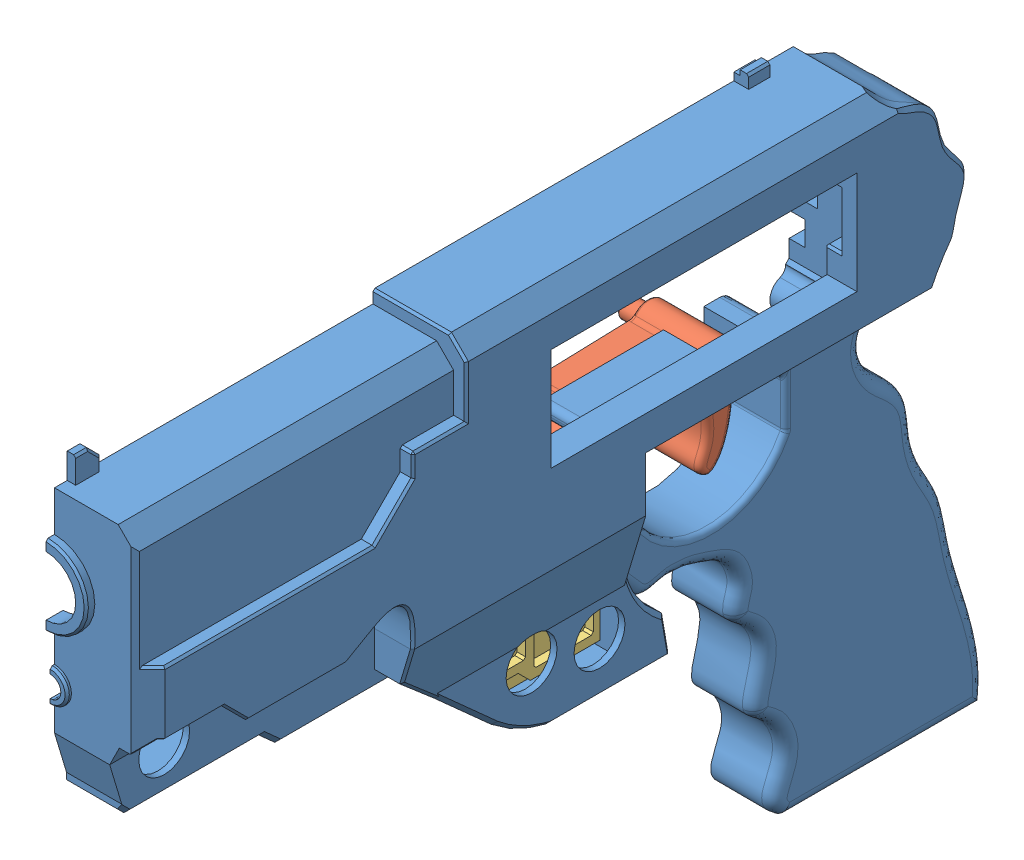
SolidWorks assembly Assemblage_en_coupe, configuration Défaut. Lengths in mm.
Overall size (37.15 144.71 215.3).
5 component instances, 5 part files, 14 mates.
Components (placement in the parent):
- pistolet_cote_circuit-1: pistolet_cote_circuit [Défaut] at (-61.6819 55.6164 215.3016) size (23.45 144.71 215.3)
- gachette_v3-1: gachette_v3 [Défaut] at (-61.6819 30.8475 67.1148) x (0 -0.031257 0.999511) z (-1 0 0) size (42.56 30.73 27.4)
- plaque_interrupteur_crosse-1: plaque_interrupteur_crosse [Défaut] at (-55.1819 -2.708 116.1316) x (0 0 1) z (-1 0 0) size (47.34 21.79 4)
- plaque_interrupteur_canon-1: plaque_interrupteur_canon [Défaut] at (-59.1819 21.0092 190.2537) x (0 0 1) z (-1 0 0) size (32.24 14.2 3.5)
- coulisseau_v3-1: coulisseau_v3 [Défaut] at (-62.3819 55.6164 150.3016) x (0 -1 0) z (0 0 -1) size (29 16 7)
Mates (geometry in assembly coordinates):
- Coaxiale1: concentric aligned: cylinder of pistolet_cote_circuit-1 through (-76.1819 30.8475 67.1148) axis (1 0 0) radius 2.7; cylinder of gachette_v3-1 through (-70.1819 30.8475 67.1148) axis (1 0 0) radius 4
- Distance1: distance = 0.8 mm anti-aligned: plane of gachette_v3-1 through (-53.1819 30.8475 67.1148) normal (1 0 0); plane of pistolet_cote_circuit-1 through (-52.3819 55.6164 215.3016) normal (-1 0 0)
- Parallèle1: parallel anti-aligned: plane of pistolet_cote_circuit-1 through (-61.6819 55.6164 93.9572) normal (0 0 1); plane of gachette_v3-1
- Parallèle2: parallel anti-aligned: plane of pistolet_cote_circuit-1 through (-61.6819 55.6164 93.9572) normal (0 0 1); plane of gachette_v3-1
- Coïncidente4: coincident anti-aligned: plane of pistolet_cote_circuit-1 through (-55.1819 55.6164 215.3016) normal (-1 0 0); plane of plaque_interrupteur_crosse-1 through (-55.1819 -2.708 116.1316) normal (1 0 0)
- Coaxiale2: concentric anti-aligned: cylinder of pistolet_cote_circuit-1 through (-50.1819 3.487 133.3016) axis (-1 0 0) radius 0.7; cylinder of plaque_interrupteur_crosse-1 through (-57.1819 3.487 133.3016) axis (1 0 0) radius 1.05
- Parallèle3: parallel anti-aligned: plane of pistolet_cote_circuit-1 through (-81.6819 74.1164 137.3016) normal (0 0 -1); plane of plaque_interrupteur_crosse-1 through (-57.1819 8.187 136.9316) normal (0 0 1)
- Coïncidente5: coincident anti-aligned: plane of pistolet_cote_circuit-1 through (-59.1819 55.6164 215.3016) normal (-1 0 0); plane of plaque_interrupteur_canon-1 through (-59.1819 21.0092 190.2537) normal (1 0 0)
- Coaxiale4: concentric anti-aligned: cylinder of pistolet_cote_circuit-1 through (-54.1819 27.6217 184.3016) axis (-1 0 0) radius 0.7; cylinder of plaque_interrupteur_canon-1 through (-60.6819 27.6217 184.3016) axis (1 0 0) radius 1.05
- Coaxiale5: concentric anti-aligned: cylinder of pistolet_cote_circuit-1 through (-54.1819 16.6217 184.3016) axis (-1 0 0) radius 0.7; cylinder of plaque_interrupteur_canon-1 through (-60.6819 16.6217 184.3016) axis (1 0 0) radius 1.05
- Coïncidente6: coincident anti-aligned: plane of pistolet_cote_circuit-1 through (-57.3819 55.6164 215.3016) normal (-1 0 0); plane of coulisseau_v3-1 through (-57.3819 70.1164 150.3016) normal (1 0 0)
- Parallèle4: parallel anti-aligned: plane of pistolet_cote_circuit-1 through (-57.3819 70.4164 167.3016) normal (0 0 -1); plane of coulisseau_v3-1 through (-62.3819 55.6164 150.3016) normal (0 0 1)
- Distance2: distance = 0.3 mm anti-aligned: plane of pistolet_cote_circuit-1 through (-57.3819 40.8164 137.3016) normal (0 1 0); plane of coulisseau_v3-1 through (-62.3819 41.1164 150.3016) normal (0 -1 0)
- Distance3: distance = 38 mm aligned: plane of pistolet_cote_circuit-1 through (-61.6819 55.6164 188.3016) normal (0 0 1); plane of coulisseau_v3-1 through (-62.3819 55.6164 150.3016) normal (0 0 1)
